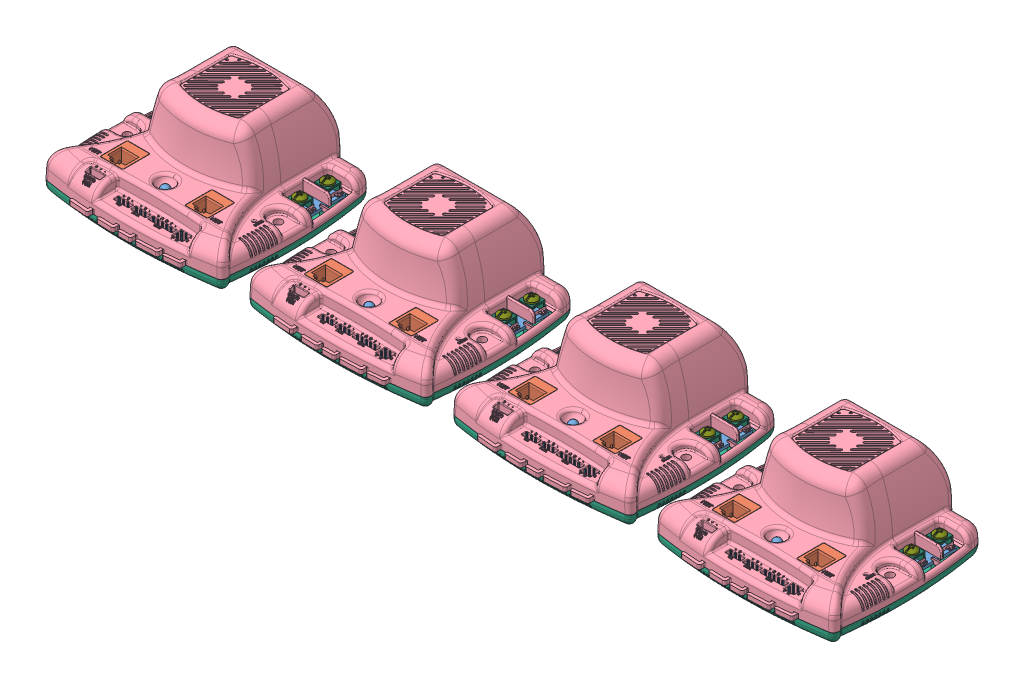
SolidWorks assembly Assem2, configuration Default. Lengths in mm.
Overall size (508 52.96 138.59).
360 component instances, 25 part files, 0 mates.
Components (placement in the parent):
- jaguar-1: jaguar [Default] at (56.1872 37.201 77.5622) size (108.73 52.96 100.91)
  - A-LM-0608-1_PCB_ASM-1: A-LM-0608-1_PCB_ASM [Default] at origin size (88.9 41.9 85.73)
    - C-JAGUAR-PCB-BOARD-1: C-JAGUAR-PCB-BOARD [Default] at origin size (88.9 1.59 85.73)
    - C-L9_RJ11-424106314-1: C-L9_RJ11-424106314 [Default] at (24.9174 8.0645 20.84) x (0 0 -1) z (1 0 0) size (15.88 18.87 15.75)
    - C-L9_RJ11-424106314-2: C-L9_RJ11-424106314 [Default] at (-24.9174 8.0645 20.84) x (0 0 -1) z (1 0 0) size (15.88 18.87 15.75)
    - C-L2-CAPACITOR-1: C-L2-CAPACITOR [Default] at (-0.0004 0 -17.78) size (20 20 20)
    - C-L10_FTS-105-02-X-DV-SA_ANY_ASM-1: C-L10_FTS-105-02-X-DV-SA_ANY_ASM [Default] at (36.0682 -2.8686 -7.8738) x (0 0 1) z (1 0 0) size (6.35 6.3 3.41)
      - T-1S15_-02_FTSH-DV_ANY-1: T-1S15_-02_FTSH-DV_ANY [Default] at (-2.54 -0.635 -0.635) x (0 0 -1) z (1 0 0) size (0.41 6.3 0.41)
      - T-1S15_-02_FTSH-DV_ANY_AF0-1: T-1S15_-02_FTSH-DV_ANY_AF0 [Default] at (2.54 -0.635 0.635) x (0 0 1) z (-1 0 0) size (0.41 6.3 0.41)
      - T-1S15_-02_FTSH-DV_ANY-2: T-1S15_-02_FTSH-DV_ANY [Default] at (-1.27 -0.635 -0.635) x (0 0 -1) z (1 0 0) size (0.41 6.3 0.41)
      - T-1S15_-02_FTSH-DV_ANY-3: T-1S15_-02_FTSH-DV_ANY [Default] at (1.27 -0.635 -0.635) x (0 0 -1) z (1 0 0) size (0.41 6.3 0.41)
      - T-1S15_-02_FTSH-DV_ANY-4: T-1S15_-02_FTSH-DV_ANY [Default] at (0 -0.635 -0.635) x (0 0 -1) z (1 0 0) size (0.41 6.3 0.41)
      - T-1S15_-02_FTSH-DV_ANY-5: T-1S15_-02_FTSH-DV_ANY [Default] at (2.54 -0.635 -0.635) x (0 0 -1) z (1 0 0) size (0.41 6.3 0.41)
      - T-1S15_-02_FTSH-DV_ANY-6: T-1S15_-02_FTSH-DV_ANY [Default] at (1.27 -0.635 0.635) x (0 0 1) z (-1 0 0) size (0.41 6.3 0.41)
      - T-1S15_-02_FTSH-DV_ANY-7: T-1S15_-02_FTSH-DV_ANY [Default] at (0 -0.635 0.635) x (0 0 1) z (-1 0 0) size (0.41 6.3 0.41)
      - T-1S15_-02_FTSH-DV_ANY-8: T-1S15_-02_FTSH-DV_ANY [Default] at (-2.54 -0.635 0.635) x (0 0 1) z (-1 0 0) size (0.41 6.3 0.41)
      - FTS-X-DV_FORMULA_ANY_AF0-1: FTS-X-DV_FORMULA_ANY_AF0 [Default] at origin size (6.35 1 3.41)
      - T-1S15_-02_FTSH-DV_ANY-9: T-1S15_-02_FTSH-DV_ANY [Default] at (-1.27 -0.635 0.635) x (0 0 1) z (-1 0 0) size (0.41 6.3 0.41)
    - L11-SSW-104-01-X-S_ASM-1: L11-SSW-104-01-X-S_ASM [Default] at (-27.6182 0 35.6196) size (8.12 11.05 2.5)
      - SSW-XX-X-1: SSW-XX-X [Default] at origin size (8.12 8.51 2.5)
      - C-08-X-1: C-08-X [Default] at (-1.27 0.508 1.2192) size (1.96 9.53 0.41)
      - C-08-X-2: C-08-X [Default] at (1.27 0.508 1.2192) size (1.96 9.53 0.41)
      - C-08-X-3: C-08-X [Default] at (3.81 0.508 1.2192) size (1.96 9.53 0.41)
    - C-L13-1X3_HEADER_ASM-1: C-L13-1X3_HEADER_ASM [Default] at (-3.5052 1.524 36.8173) size (7.62 10.92 2.54)
      - C-HEADER-3PIN-BODY-1: C-HEADER-3PIN-BODY [Default] at origin size (7.62 2.54 2.54)
      - C-T-HEADER-PIN-1: C-T-HEADER-PIN [Default] at (-6.35 -2.0599 0) x (0 0 1) z (-1 0 0) size (0.64 10.92 0.64)
      - C-T-HEADER-PIN-2: C-T-HEADER-PIN [Default] at (-3.81 -2.0599 0) x (0 0 1) z (-1 0 0) size (0.64 10.92 0.64)
      - C-T-HEADER-PIN-3: C-T-HEADER-PIN [Default] at (-8.89 -2.0599 0) x (0 0 1) z (-1 0 0) size (0.64 10.92 0.64)
    - C-L13-1X3_HEADER_ASM-2: C-L13-1X3_HEADER_ASM [Default] at (6.6548 1.524 36.8173) size (7.62 10.92 2.54)
      - C-HEADER-3PIN-BODY-1: C-HEADER-3PIN-BODY [Default] at origin size (7.62 2.54 2.54)
      - C-T-HEADER-PIN-1: C-T-HEADER-PIN [Default] at (-6.35 -2.0599 0) x (0 0 1) z (-1 0 0) size (0.64 10.92 0.64)
      - C-T-HEADER-PIN-2: C-T-HEADER-PIN [Default] at (-3.81 -2.0599 0) x (0 0 1) z (-1 0 0) size (0.64 10.92 0.64)
      - C-T-HEADER-PIN-3: C-T-HEADER-PIN [Default] at (-8.89 -2.0599 0) x (0 0 1) z (-1 0 0) size (0.64 10.92 0.64)
    - C-L12-1X5_HEADER_ASM-1: C-L12-1X5_HEADER_ASM [Default] at (16.8148 1.524 36.8173) size (12.7 10.92 2.54)
      - C-T-HEADER-PIN-1: C-T-HEADER-PIN [Default] at (-6.35 -2.0599 0) x (0 0 1) z (-1 0 0) size (0.64 10.92 0.64)
      - C-T-HEADER-PIN-2: C-T-HEADER-PIN [Default] at (-3.81 -2.0599 0) x (0 0 1) z (-1 0 0) size (0.64 10.92 0.64)
      - C-T-HEADER-PIN-3: C-T-HEADER-PIN [Default] at (1.27 -2.0599 0) x (0 0 1) z (-1 0 0) size (0.64 10.92 0.64)
      - C-T-HEADER-PIN-4: C-T-HEADER-PIN [Default] at (-8.89 -2.0599 0) x (0 0 1) z (-1 0 0) size (0.64 10.92 0.64)
      - C-T-HEADER-PIN-5: C-T-HEADER-PIN [Default] at (-1.27 -2.0599 0) x (0 0 1) z (-1 0 0) size (0.64 10.92 0.64)
      - C-TSW-XX-S_FORMULA_ANY-5-1: C-TSW-XX-S_FORMULA_ANY-5 [Default] at origin size (12.7 2.54 2.54)
    - C-U1_LUMINARY-CHIP-1: C-U1_LUMINARY-CHIP [Default] at (9.887 0 22.86) size (12 1.45 12)
    - C-BUTTON-SWITCH_ASM-1: C-BUTTON-SWITCH_ASM [Default] at (40.8559 0 10.668) size (6 5 6)
      - C-BS-SWITCH-BASE-1: C-BS-SWITCH-BASE [Default] at origin size (6 4 6)
      - C-BS-EXTENSION-1: C-BS-EXTENSION [Default] at origin size (3.5 1.9 3.5)
    - C-SCREW-TERMINAL-7701_ASM-1: C-SCREW-TERMINAL-7701_ASM [Default] at (39.2172 -5.0038 -17.7792) size (7.87 10.19 7.87)
      - C-ST-7701-BASE-1: C-ST-7701-BASE [Default] at origin size (7.87 7.76 7.87)
      - 6-PH-SCREW-25-1: 6-PH-SCREW-25 [Default] at (0 11.176 0) size (6.86 7.18 6.86)
    - C-SCREW-TERMINAL-7701_ASM-2: C-SCREW-TERMINAL-7701_ASM [Default] at (39.2172 -5.0038 -34.2892) size (7.87 10.19 7.87)
      - C-ST-7701-BASE-1: C-ST-7701-BASE [Default] at origin size (7.87 7.76 7.87)
      - 6-PH-SCREW-25-1: 6-PH-SCREW-25 [Default] at (0 11.176 0) size (6.86 7.18 6.86)
    - C-SCREW-TERMINAL-7701_ASM-3: C-SCREW-TERMINAL-7701_ASM [Default] at (-39.2172 -5.0038 -34.2892) size (7.87 10.19 7.87)
      - C-ST-7701-BASE-1: C-ST-7701-BASE [Default] at origin size (7.87 7.76 7.87)
      - 6-PH-SCREW-25-1: 6-PH-SCREW-25 [Default] at (0 11.176 0) size (6.86 7.18 6.86)
    - C-SCREW-TERMINAL-7701_ASM-4: C-SCREW-TERMINAL-7701_ASM [Default] at (-39.2172 -5.0038 -17.7792) size (7.87 10.19 7.87)
      - C-ST-7701-BASE-1: C-ST-7701-BASE [Default] at origin size (7.87 7.76 7.87)
      - 6-PH-SCREW-25-1: 6-PH-SCREW-25 [Default] at (0 11.176 0) size (6.86 7.18 6.86)
    - C-Q1-Q12_MOSFET-1: C-Q1-Q12_MOSFET [Default] at (0.2539 4.8006 -35.56) x (1 0 0.000017) z (-0.000017 0 1) size (4.57 20.75 10.36)
    - C-Q1-Q12_MOSFET-2: C-Q1-Q12_MOSFET [Default] at (8.9829 4.8006 -32.9335) x (0.866017 0 0.500015) z (-0.500015 0 0.866017) size (4.57 20.75 10.36)
    - C-Q1-Q12_MOSFET-3: C-Q1-Q12_MOSFET [Default] at (8.7964 4.8006 -2.2451) x (-0.866035 0 0.499983) z (-0.499983 0 -0.866035) size (4.57 20.75 10.36)
    - C-Q1-Q12_MOSFET-4: C-Q1-Q12_MOSFET [Default] at (-0.2547 4.8006 0) x (-1 0 -0.000017) z (0.000017 0 -1) size (4.57 20.75 10.36)
    - C-Q1-Q12_MOSFET-5: C-Q1-Q12_MOSFET [Default] at (-9.1106 4.8006 -2.4995) x (-0.866018 0 -0.500013) z (0.500013 0 -0.866018) size (4.57 20.75 10.36)
    - C-Q1-Q12_MOSFET-6: C-Q1-Q12_MOSFET [Default] at (-8.4161 4.8006 -33.3149) x (0.866034 0 -0.499985) z (0.499985 0 0.866034) size (4.57 20.75 10.36)
    - C-Q1-Q12_MOSFET-7: C-Q1-Q12_MOSFET [Default] at (15.4531 4.8006 -26.8897) x (-0.499985 0 -0.866034) z (0.866034 0 -0.499985) size (4.57 20.75 10.36)
    - C-Q1-Q12_MOSFET-8: C-Q1-Q12_MOSFET [Default] at (17.7796 4.8006 -18.0337) x (0.000017 0 -1) z (1 0 0.000017) size (4.57 20.75 10.36)
    - C-Q1-Q12_MOSFET-9: C-Q1-Q12_MOSFET [Default] at (15.7068 4.8006 -9.1097) x (0.500015 0 -0.866017) z (0.866017 0 0.500015) size (4.57 20.75 10.36)
    - C-Q1-Q12_MOSFET-10: C-Q1-Q12_MOSFET [Default] at (-15.4538 4.8006 -8.6703) x (0.499985 0 0.866034) z (-0.866034 0 0.499985) size (4.57 20.75 10.36)
    - C-Q1-Q12_MOSFET-11: C-Q1-Q12_MOSFET [Default] at (-17.7804 4.8006 -17.5263) x (-0.000017 0 1) z (-1 0 -0.000017) size (4.57 20.75 10.36)
    - C-Q1-Q12_MOSFET-12: C-Q1-Q12_MOSFET [Default] at (-15.7075 4.8006 -26.4503) x (-0.500015 0 0.866017) z (-0.866017 0 -0.500015) size (4.57 20.75 10.36)
    - C-Q1-Q12_MOSFET-13: C-Q1-Q12_MOSFET [Default] at (0.2539 4.8006 -35.56) size (4.57 20.75 10.36)
    - P-LM-0608-1-003_MOSFET-RING-1: P-LM-0608-1-003_MOSFET-RING [Default] at origin size (51.07 7.69 51.07)
    - I15_59-1: I15_59 [Default] at (0 5.8 22.11) size (5.9 13.4 5.84)
    - D4010-1: D4010 [Default] at (-0.0004 25.4 -17.78) x (0.000017 0 -1) z (-1 0 -0.000017) size (40 11.76 40)
    - C-L13-1X2_HEADER_ASM-1: C-L13-1X2_HEADER_ASM [Default] at (32.0548 1.524 35.5473) size (5.08 10.92 2.54)
      - C-HEADER-2PIN-BODY-1: C-HEADER-2PIN-BODY [Default] at origin size (5.08 2.54 2.54)
      - C-T-HEADER-PIN-1: C-T-HEADER-PIN [Default] at (-6.35 -2.0599 0) x (0 0 1) z (-1 0 0) size (0.64 10.92 0.64)
      - C-T-HEADER-PIN-2: C-T-HEADER-PIN [Default] at (-8.89 -2.0599 0) x (0 0 1) z (-1 0 0) size (0.64 10.92 0.64)
    - C-L13-1X2_HEADER_ASM-2: C-L13-1X2_HEADER_ASM [Default] at (32.0548 1.524 38.0873) size (5.08 10.92 2.54)
      - C-HEADER-2PIN-BODY-1: C-HEADER-2PIN-BODY [Default] at origin size (5.08 2.54 2.54)
      - C-T-HEADER-PIN-1: C-T-HEADER-PIN [Default] at (-6.35 -2.0599 0) x (0 0 1) z (-1 0 0) size (0.64 10.92 0.64)
      - C-T-HEADER-PIN-2: C-T-HEADER-PIN [Default] at (-8.89 -2.0599 0) x (0 0 1) z (-1 0 0) size (0.64 10.92 0.64)
  - 217-3367-001-1: 217-3367-001 [Default] at origin size (108.73 46.49 100.91)
  - 4-PH-SCREW-58-1: 4-PH-SCREW-58 [Default] at (-16.0007 25.4 -1.7803) x (-1 0 0) z (0 0 1) size (5.56 17.84 5.56)
  - 217-3367-002-1: 217-3367-002 [Default] at origin size (107.95 8.08 97.61)
  - 4-PH-SCREW-5-1: 4-PH-SCREW-5 [Default] at (46.482 -3.7084 36.4715) x (-1 0 0) z (0 0 1) size (5.56 14.66 5.56)
  - 4-PH-SCREW-5-2: 4-PH-SCREW-5 [Default] at (43.9521 -3.7084 -44.717) x (-1 0 0) z (0 0 1) size (5.56 14.66 5.56)
  - 4-PH-SCREW-5-3: 4-PH-SCREW-5 [Default] at (-43.9521 -3.7084 -44.717) x (-1 0 0) z (0 0 1) size (5.56 14.66 5.56)
  - 4-PH-SCREW-5-4: 4-PH-SCREW-5 [Default] at (-46.482 -3.7084 36.4715) x (-1 0 0) z (0 0 1) size (5.56 14.66 5.56)
  - 4-PH-SCREW-58-2: 4-PH-SCREW-58 [Default] at (-16.0001 25.4 -33.7803) x (-1 0 0) z (0 0 1) size (5.56 17.84 5.56)
  - 4-PH-SCREW-58-3: 4-PH-SCREW-58 [Default] at (15.9999 25.4 -33.7797) x (-1 0 0) z (0 0 1) size (5.56 17.84 5.56)
  - 4-PH-SCREW-58-4: 4-PH-SCREW-58 [Default] at (15.9993 25.4 -1.7797) x (-1 0 0) z (0 0 1) size (5.56 17.84 5.56)
- jaguar-2: jaguar [Default] at (176.1872 37.201 77.5622) size (108.73 52.96 100.91)
  - A-LM-0608-1_PCB_ASM-1: A-LM-0608-1_PCB_ASM [Default] at origin size (88.9 41.9 85.73)
    - C-JAGUAR-PCB-BOARD-1: C-JAGUAR-PCB-BOARD [Default] at origin size (88.9 1.59 85.73)
    - C-L9_RJ11-424106314-1: C-L9_RJ11-424106314 [Default] at (24.9174 8.0645 20.84) x (0 0 -1) z (1 0 0) size (15.88 18.87 15.75)
    - C-L9_RJ11-424106314-2: C-L9_RJ11-424106314 [Default] at (-24.9174 8.0645 20.84) x (0 0 -1) z (1 0 0) size (15.88 18.87 15.75)
    - C-L2-CAPACITOR-1: C-L2-CAPACITOR [Default] at (-0.0004 0 -17.78) size (20 20 20)
    - C-L10_FTS-105-02-X-DV-SA_ANY_ASM-1: C-L10_FTS-105-02-X-DV-SA_ANY_ASM [Default] at (36.0682 -2.8686 -7.8738) x (0 0 1) z (1 0 0) size (6.35 6.3 3.41)
      - T-1S15_-02_FTSH-DV_ANY-1: T-1S15_-02_FTSH-DV_ANY [Default] at (-2.54 -0.635 -0.635) x (0 0 -1) z (1 0 0) size (0.41 6.3 0.41)
      - T-1S15_-02_FTSH-DV_ANY_AF0-1: T-1S15_-02_FTSH-DV_ANY_AF0 [Default] at (2.54 -0.635 0.635) x (0 0 1) z (-1 0 0) size (0.41 6.3 0.41)
      - T-1S15_-02_FTSH-DV_ANY-2: T-1S15_-02_FTSH-DV_ANY [Default] at (-1.27 -0.635 -0.635) x (0 0 -1) z (1 0 0) size (0.41 6.3 0.41)
      - T-1S15_-02_FTSH-DV_ANY-3: T-1S15_-02_FTSH-DV_ANY [Default] at (1.27 -0.635 -0.635) x (0 0 -1) z (1 0 0) size (0.41 6.3 0.41)
      - T-1S15_-02_FTSH-DV_ANY-4: T-1S15_-02_FTSH-DV_ANY [Default] at (0 -0.635 -0.635) x (0 0 -1) z (1 0 0) size (0.41 6.3 0.41)
      - T-1S15_-02_FTSH-DV_ANY-5: T-1S15_-02_FTSH-DV_ANY [Default] at (2.54 -0.635 -0.635) x (0 0 -1) z (1 0 0) size (0.41 6.3 0.41)
      - T-1S15_-02_FTSH-DV_ANY-6: T-1S15_-02_FTSH-DV_ANY [Default] at (1.27 -0.635 0.635) x (0 0 1) z (-1 0 0) size (0.41 6.3 0.41)
      - T-1S15_-02_FTSH-DV_ANY-7: T-1S15_-02_FTSH-DV_ANY [Default] at (0 -0.635 0.635) x (0 0 1) z (-1 0 0) size (0.41 6.3 0.41)
      - T-1S15_-02_FTSH-DV_ANY-8: T-1S15_-02_FTSH-DV_ANY [Default] at (-2.54 -0.635 0.635) x (0 0 1) z (-1 0 0) size (0.41 6.3 0.41)
      - FTS-X-DV_FORMULA_ANY_AF0-1: FTS-X-DV_FORMULA_ANY_AF0 [Default] at origin size (6.35 1 3.41)
      - T-1S15_-02_FTSH-DV_ANY-9: T-1S15_-02_FTSH-DV_ANY [Default] at (-1.27 -0.635 0.635) x (0 0 1) z (-1 0 0) size (0.41 6.3 0.41)
    - L11-SSW-104-01-X-S_ASM-1: L11-SSW-104-01-X-S_ASM [Default] at (-27.6182 0 35.6196) size (8.12 11.05 2.5)
      - SSW-XX-X-1: SSW-XX-X [Default] at origin size (8.12 8.51 2.5)
      - C-08-X-1: C-08-X [Default] at (-1.27 0.508 1.2192) size (1.96 9.53 0.41)
      - C-08-X-2: C-08-X [Default] at (1.27 0.508 1.2192) size (1.96 9.53 0.41)
      - C-08-X-3: C-08-X [Default] at (3.81 0.508 1.2192) size (1.96 9.53 0.41)
    - C-L13-1X3_HEADER_ASM-1: C-L13-1X3_HEADER_ASM [Default] at (-3.5052 1.524 36.8173) size (7.62 10.92 2.54)
      - C-HEADER-3PIN-BODY-1: C-HEADER-3PIN-BODY [Default] at origin size (7.62 2.54 2.54)
      - C-T-HEADER-PIN-1: C-T-HEADER-PIN [Default] at (-6.35 -2.0599 0) x (0 0 1) z (-1 0 0) size (0.64 10.92 0.64)
      - C-T-HEADER-PIN-2: C-T-HEADER-PIN [Default] at (-3.81 -2.0599 0) x (0 0 1) z (-1 0 0) size (0.64 10.92 0.64)
      - C-T-HEADER-PIN-3: C-T-HEADER-PIN [Default] at (-8.89 -2.0599 0) x (0 0 1) z (-1 0 0) size (0.64 10.92 0.64)
    - C-L13-1X3_HEADER_ASM-2: C-L13-1X3_HEADER_ASM [Default] at (6.6548 1.524 36.8173) size (7.62 10.92 2.54)
      - C-HEADER-3PIN-BODY-1: C-HEADER-3PIN-BODY [Default] at origin size (7.62 2.54 2.54)
      - C-T-HEADER-PIN-1: C-T-HEADER-PIN [Default] at (-6.35 -2.0599 0) x (0 0 1) z (-1 0 0) size (0.64 10.92 0.64)
      - C-T-HEADER-PIN-2: C-T-HEADER-PIN [Default] at (-3.81 -2.0599 0) x (0 0 1) z (-1 0 0) size (0.64 10.92 0.64)
      - C-T-HEADER-PIN-3: C-T-HEADER-PIN [Default] at (-8.89 -2.0599 0) x (0 0 1) z (-1 0 0) size (0.64 10.92 0.64)
    - C-L12-1X5_HEADER_ASM-1: C-L12-1X5_HEADER_ASM [Default] at (16.8148 1.524 36.8173) size (12.7 10.92 2.54)
      - C-T-HEADER-PIN-1: C-T-HEADER-PIN [Default] at (-6.35 -2.0599 0) x (0 0 1) z (-1 0 0) size (0.64 10.92 0.64)
      - C-T-HEADER-PIN-2: C-T-HEADER-PIN [Default] at (-3.81 -2.0599 0) x (0 0 1) z (-1 0 0) size (0.64 10.92 0.64)
      - C-T-HEADER-PIN-3: C-T-HEADER-PIN [Default] at (1.27 -2.0599 0) x (0 0 1) z (-1 0 0) size (0.64 10.92 0.64)
      - C-T-HEADER-PIN-4: C-T-HEADER-PIN [Default] at (-8.89 -2.0599 0) x (0 0 1) z (-1 0 0) size (0.64 10.92 0.64)
      - C-T-HEADER-PIN-5: C-T-HEADER-PIN [Default] at (-1.27 -2.0599 0) x (0 0 1) z (-1 0 0) size (0.64 10.92 0.64)
      - C-TSW-XX-S_FORMULA_ANY-5-1: C-TSW-XX-S_FORMULA_ANY-5 [Default] at origin size (12.7 2.54 2.54)
    - C-U1_LUMINARY-CHIP-1: C-U1_LUMINARY-CHIP [Default] at (9.887 0 22.86) size (12 1.45 12)
    - C-BUTTON-SWITCH_ASM-1: C-BUTTON-SWITCH_ASM [Default] at (40.8559 0 10.668) size (6 5 6)
      - C-BS-SWITCH-BASE-1: C-BS-SWITCH-BASE [Default] at origin size (6 4 6)
      - C-BS-EXTENSION-1: C-BS-EXTENSION [Default] at origin size (3.5 1.9 3.5)
    - C-SCREW-TERMINAL-7701_ASM-1: C-SCREW-TERMINAL-7701_ASM [Default] at (39.2172 -5.0038 -17.7792) size (7.87 10.19 7.87)
      - C-ST-7701-BASE-1: C-ST-7701-BASE [Default] at origin size (7.87 7.76 7.87)
      - 6-PH-SCREW-25-1: 6-PH-SCREW-25 [Default] at (0 11.176 0) size (6.86 7.18 6.86)
    - C-SCREW-TERMINAL-7701_ASM-2: C-SCREW-TERMINAL-7701_ASM [Default] at (39.2172 -5.0038 -34.2892) size (7.87 10.19 7.87)
      - C-ST-7701-BASE-1: C-ST-7701-BASE [Default] at origin size (7.87 7.76 7.87)
      - 6-PH-SCREW-25-1: 6-PH-SCREW-25 [Default] at (0 11.176 0) size (6.86 7.18 6.86)
    - C-SCREW-TERMINAL-7701_ASM-3: C-SCREW-TERMINAL-7701_ASM [Default] at (-39.2172 -5.0038 -34.2892) size (7.87 10.19 7.87)
      - C-ST-7701-BASE-1: C-ST-7701-BASE [Default] at origin size (7.87 7.76 7.87)
      - 6-PH-SCREW-25-1: 6-PH-SCREW-25 [Default] at (0 11.176 0) size (6.86 7.18 6.86)
    - C-SCREW-TERMINAL-7701_ASM-4: C-SCREW-TERMINAL-7701_ASM [Default] at (-39.2172 -5.0038 -17.7792) size (7.87 10.19 7.87)
      - C-ST-7701-BASE-1: C-ST-7701-BASE [Default] at origin size (7.87 7.76 7.87)
      - 6-PH-SCREW-25-1: 6-PH-SCREW-25 [Default] at (0 11.176 0) size (6.86 7.18 6.86)
    - C-Q1-Q12_MOSFET-1: C-Q1-Q12_MOSFET [Default] at (0.2539 4.8006 -35.56) x (1 0 0.000017) z (-0.000017 0 1) size (4.57 20.75 10.36)
    - C-Q1-Q12_MOSFET-2: C-Q1-Q12_MOSFET [Default] at (8.9829 4.8006 -32.9335) x (0.866017 0 0.500015) z (-0.500015 0 0.866017) size (4.57 20.75 10.36)
    - C-Q1-Q12_MOSFET-3: C-Q1-Q12_MOSFET [Default] at (8.7964 4.8006 -2.2451) x (-0.866035 0 0.499983) z (-0.499983 0 -0.866035) size (4.57 20.75 10.36)
    - C-Q1-Q12_MOSFET-4: C-Q1-Q12_MOSFET [Default] at (-0.2547 4.8006 0) x (-1 0 -0.000017) z (0.000017 0 -1) size (4.57 20.75 10.36)
    - C-Q1-Q12_MOSFET-5: C-Q1-Q12_MOSFET [Default] at (-9.1106 4.8006 -2.4995) x (-0.866018 0 -0.500013) z (0.500013 0 -0.866018) size (4.57 20.75 10.36)
    - C-Q1-Q12_MOSFET-6: C-Q1-Q12_MOSFET [Default] at (-8.4161 4.8006 -33.3149) x (0.866034 0 -0.499985) z (0.499985 0 0.866034) size (4.57 20.75 10.36)
    - C-Q1-Q12_MOSFET-7: C-Q1-Q12_MOSFET [Default] at (15.4531 4.8006 -26.8897) x (-0.499985 0 -0.866034) z (0.866034 0 -0.499985) size (4.57 20.75 10.36)
    - C-Q1-Q12_MOSFET-8: C-Q1-Q12_MOSFET [Default] at (17.7796 4.8006 -18.0337) x (0.000017 0 -1) z (1 0 0.000017) size (4.57 20.75 10.36)
    - C-Q1-Q12_MOSFET-9: C-Q1-Q12_MOSFET [Default] at (15.7068 4.8006 -9.1097) x (0.500015 0 -0.866017) z (0.866017 0 0.500015) size (4.57 20.75 10.36)
    - C-Q1-Q12_MOSFET-10: C-Q1-Q12_MOSFET [Default] at (-15.4538 4.8006 -8.6703) x (0.499985 0 0.866034) z (-0.866034 0 0.499985) size (4.57 20.75 10.36)
    - C-Q1-Q12_MOSFET-11: C-Q1-Q12_MOSFET [Default] at (-17.7804 4.8006 -17.5263) x (-0.000017 0 1) z (-1 0 -0.000017) size (4.57 20.75 10.36)
    - C-Q1-Q12_MOSFET-12: C-Q1-Q12_MOSFET [Default] at (-15.7075 4.8006 -26.4503) x (-0.500015 0 0.866017) z (-0.866017 0 -0.500015) size (4.57 20.75 10.36)
    - C-Q1-Q12_MOSFET-13: C-Q1-Q12_MOSFET [Default] at (0.2539 4.8006 -35.56) size (4.57 20.75 10.36)
    - P-LM-0608-1-003_MOSFET-RING-1: P-LM-0608-1-003_MOSFET-RING [Default] at origin size (51.07 7.69 51.07)
    - I15_59-1: I15_59 [Default] at (0 5.8 22.11) size (5.9 13.4 5.84)
    - D4010-1: D4010 [Default] at (-0.0004 25.4 -17.78) x (0.000017 0 -1) z (-1 0 -0.000017) size (40 11.76 40)
    - C-L13-1X2_HEADER_ASM-1: C-L13-1X2_HEADER_ASM [Default] at (32.0548 1.524 35.5473) size (5.08 10.92 2.54)
      - C-HEADER-2PIN-BODY-1: C-HEADER-2PIN-BODY [Default] at origin size (5.08 2.54 2.54)
      - C-T-HEADER-PIN-1: C-T-HEADER-PIN [Default] at (-6.35 -2.0599 0) x (0 0 1) z (-1 0 0) size (0.64 10.92 0.64)
      - C-T-HEADER-PIN-2: C-T-HEADER-PIN [Default] at (-8.89 -2.0599 0) x (0 0 1) z (-1 0 0) size (0.64 10.92 0.64)
    - C-L13-1X2_HEADER_ASM-2: C-L13-1X2_HEADER_ASM [Default] at (32.0548 1.524 38.0873) size (5.08 10.92 2.54)
      - C-HEADER-2PIN-BODY-1: C-HEADER-2PIN-BODY [Default] at origin size (5.08 2.54 2.54)
      - C-T-HEADER-PIN-1: C-T-HEADER-PIN [Default] at (-6.35 -2.0599 0) x (0 0 1) z (-1 0 0) size (0.64 10.92 0.64)
      - C-T-HEADER-PIN-2: C-T-HEADER-PIN [Default] at (-8.89 -2.0599 0) x (0 0 1) z (-1 0 0) size (0.64 10.92 0.64)
  - 217-3367-001-1: 217-3367-001 [Default] at origin size (108.73 46.49 100.91)
  - 4-PH-SCREW-58-1: 4-PH-SCREW-58 [Default] at (-16.0007 25.4 -1.7803) x (-1 0 0) z (0 0 1) size (5.56 17.84 5.56)
  - 217-3367-002-1: 217-3367-002 [Default] at origin size (107.95 8.08 97.61)
  - 4-PH-SCREW-5-1: 4-PH-SCREW-5 [Default] at (46.482 -3.7084 36.4715) x (-1 0 0) z (0 0 1) size (5.56 14.66 5.56)
  - 4-PH-SCREW-5-2: 4-PH-SCREW-5 [Default] at (43.9521 -3.7084 -44.717) x (-1 0 0) z (0 0 1) size (5.56 14.66 5.56)
  - 4-PH-SCREW-5-3: 4-PH-SCREW-5 [Default] at (-43.9521 -3.7084 -44.717) x (-1 0 0) z (0 0 1) size (5.56 14.66 5.56)
  - 4-PH-SCREW-5-4: 4-PH-SCREW-5 [Default] at (-46.482 -3.7084 36.4715) x (-1 0 0) z (0 0 1) size (5.56 14.66 5.56)
  - 4-PH-SCREW-58-2: 4-PH-SCREW-58 [Default] at (-16.0001 25.4 -33.7803) x (-1 0 0) z (0 0 1) size (5.56 17.84 5.56)
  - 4-PH-SCREW-58-3: 4-PH-SCREW-58 [Default] at (15.9999 25.4 -33.7797) x (-1 0 0) z (0 0 1) size (5.56 17.84 5.56)
  - 4-PH-SCREW-58-4: 4-PH-SCREW-58 [Default] at (15.9993 25.4 -1.7797) x (-1 0 0) z (0 0 1) size (5.56 17.84 5.56)
- jaguar-3: jaguar [Default] at (296.1872 37.201 77.5622) size (108.73 52.96 100.91)
  - A-LM-0608-1_PCB_ASM-1: A-LM-0608-1_PCB_ASM [Default] at origin size (88.9 41.9 85.73)
    - C-JAGUAR-PCB-BOARD-1: C-JAGUAR-PCB-BOARD [Default] at origin size (88.9 1.59 85.73)
    - C-L9_RJ11-424106314-1: C-L9_RJ11-424106314 [Default] at (24.9174 8.0645 20.84) x (0 0 -1) z (1 0 0) size (15.88 18.87 15.75)
    - C-L9_RJ11-424106314-2: C-L9_RJ11-424106314 [Default] at (-24.9174 8.0645 20.84) x (0 0 -1) z (1 0 0) size (15.88 18.87 15.75)
    - C-L2-CAPACITOR-1: C-L2-CAPACITOR [Default] at (-0.0004 0 -17.78) size (20 20 20)
    - C-L10_FTS-105-02-X-DV-SA_ANY_ASM-1: C-L10_FTS-105-02-X-DV-SA_ANY_ASM [Default] at (36.0682 -2.8686 -7.8738) x (0 0 1) z (1 0 0) size (6.35 6.3 3.41)
      - T-1S15_-02_FTSH-DV_ANY-1: T-1S15_-02_FTSH-DV_ANY [Default] at (-2.54 -0.635 -0.635) x (0 0 -1) z (1 0 0) size (0.41 6.3 0.41)
      - T-1S15_-02_FTSH-DV_ANY_AF0-1: T-1S15_-02_FTSH-DV_ANY_AF0 [Default] at (2.54 -0.635 0.635) x (0 0 1) z (-1 0 0) size (0.41 6.3 0.41)
      - T-1S15_-02_FTSH-DV_ANY-2: T-1S15_-02_FTSH-DV_ANY [Default] at (-1.27 -0.635 -0.635) x (0 0 -1) z (1 0 0) size (0.41 6.3 0.41)
      - T-1S15_-02_FTSH-DV_ANY-3: T-1S15_-02_FTSH-DV_ANY [Default] at (1.27 -0.635 -0.635) x (0 0 -1) z (1 0 0) size (0.41 6.3 0.41)
      - T-1S15_-02_FTSH-DV_ANY-4: T-1S15_-02_FTSH-DV_ANY [Default] at (0 -0.635 -0.635) x (0 0 -1) z (1 0 0) size (0.41 6.3 0.41)
      - T-1S15_-02_FTSH-DV_ANY-5: T-1S15_-02_FTSH-DV_ANY [Default] at (2.54 -0.635 -0.635) x (0 0 -1) z (1 0 0) size (0.41 6.3 0.41)
      - T-1S15_-02_FTSH-DV_ANY-6: T-1S15_-02_FTSH-DV_ANY [Default] at (1.27 -0.635 0.635) x (0 0 1) z (-1 0 0) size (0.41 6.3 0.41)
      - T-1S15_-02_FTSH-DV_ANY-7: T-1S15_-02_FTSH-DV_ANY [Default] at (0 -0.635 0.635) x (0 0 1) z (-1 0 0) size (0.41 6.3 0.41)
      - T-1S15_-02_FTSH-DV_ANY-8: T-1S15_-02_FTSH-DV_ANY [Default] at (-2.54 -0.635 0.635) x (0 0 1) z (-1 0 0) size (0.41 6.3 0.41)
      - FTS-X-DV_FORMULA_ANY_AF0-1: FTS-X-DV_FORMULA_ANY_AF0 [Default] at origin size (6.35 1 3.41)
      - T-1S15_-02_FTSH-DV_ANY-9: T-1S15_-02_FTSH-DV_ANY [Default] at (-1.27 -0.635 0.635) x (0 0 1) z (-1 0 0) size (0.41 6.3 0.41)
    - L11-SSW-104-01-X-S_ASM-1: L11-SSW-104-01-X-S_ASM [Default] at (-27.6182 0 35.6196) size (8.12 11.05 2.5)
      - SSW-XX-X-1: SSW-XX-X [Default] at origin size (8.12 8.51 2.5)
      - C-08-X-1: C-08-X [Default] at (-1.27 0.508 1.2192) size (1.96 9.53 0.41)
      - C-08-X-2: C-08-X [Default] at (1.27 0.508 1.2192) size (1.96 9.53 0.41)
      - C-08-X-3: C-08-X [Default] at (3.81 0.508 1.2192) size (1.96 9.53 0.41)
    - C-L13-1X3_HEADER_ASM-1: C-L13-1X3_HEADER_ASM [Default] at (-3.5052 1.524 36.8173) size (7.62 10.92 2.54)
      - C-HEADER-3PIN-BODY-1: C-HEADER-3PIN-BODY [Default] at origin size (7.62 2.54 2.54)
      - C-T-HEADER-PIN-1: C-T-HEADER-PIN [Default] at (-6.35 -2.0599 0) x (0 0 1) z (-1 0 0) size (0.64 10.92 0.64)
      - C-T-HEADER-PIN-2: C-T-HEADER-PIN [Default] at (-3.81 -2.0599 0) x (0 0 1) z (-1 0 0) size (0.64 10.92 0.64)
      - C-T-HEADER-PIN-3: C-T-HEADER-PIN [Default] at (-8.89 -2.0599 0) x (0 0 1) z (-1 0 0) size (0.64 10.92 0.64)
    - C-L13-1X3_HEADER_ASM-2: C-L13-1X3_HEADER_ASM [Default] at (6.6548 1.524 36.8173) size (7.62 10.92 2.54)
      - C-HEADER-3PIN-BODY-1: C-HEADER-3PIN-BODY [Default] at origin size (7.62 2.54 2.54)
      - C-T-HEADER-PIN-1: C-T-HEADER-PIN [Default] at (-6.35 -2.0599 0) x (0 0 1) z (-1 0 0) size (0.64 10.92 0.64)
      - C-T-HEADER-PIN-2: C-T-HEADER-PIN [Default] at (-3.81 -2.0599 0) x (0 0 1) z (-1 0 0) size (0.64 10.92 0.64)
      - C-T-HEADER-PIN-3: C-T-HEADER-PIN [Default] at (-8.89 -2.0599 0) x (0 0 1) z (-1 0 0) size (0.64 10.92 0.64)
    - C-L12-1X5_HEADER_ASM-1: C-L12-1X5_HEADER_ASM [Default] at (16.8148 1.524 36.8173) size (12.7 10.92 2.54)
      - C-T-HEADER-PIN-1: C-T-HEADER-PIN [Default] at (-6.35 -2.0599 0) x (0 0 1) z (-1 0 0) size (0.64 10.92 0.64)
      - C-T-HEADER-PIN-2: C-T-HEADER-PIN [Default] at (-3.81 -2.0599 0) x (0 0 1) z (-1 0 0) size (0.64 10.92 0.64)
      - C-T-HEADER-PIN-3: C-T-HEADER-PIN [Default] at (1.27 -2.0599 0) x (0 0 1) z (-1 0 0) size (0.64 10.92 0.64)
      - C-T-HEADER-PIN-4: C-T-HEADER-PIN [Default] at (-8.89 -2.0599 0) x (0 0 1) z (-1 0 0) size (0.64 10.92 0.64)
      - C-T-HEADER-PIN-5: C-T-HEADER-PIN [Default] at (-1.27 -2.0599 0) x (0 0 1) z (-1 0 0) size (0.64 10.92 0.64)
      - C-TSW-XX-S_FORMULA_ANY-5-1: C-TSW-XX-S_FORMULA_ANY-5 [Default] at origin size (12.7 2.54 2.54)
    - C-U1_LUMINARY-CHIP-1: C-U1_LUMINARY-CHIP [Default] at (9.887 0 22.86) size (12 1.45 12)
    - C-BUTTON-SWITCH_ASM-1: C-BUTTON-SWITCH_ASM [Default] at (40.8559 0 10.668) size (6 5 6)
      - C-BS-SWITCH-BASE-1: C-BS-SWITCH-BASE [Default] at origin size (6 4 6)
      - C-BS-EXTENSION-1: C-BS-EXTENSION [Default] at origin size (3.5 1.9 3.5)
    - C-SCREW-TERMINAL-7701_ASM-1: C-SCREW-TERMINAL-7701_ASM [Default] at (39.2172 -5.0038 -17.7792) size (7.87 10.19 7.87)
      - C-ST-7701-BASE-1: C-ST-7701-BASE [Default] at origin size (7.87 7.76 7.87)
      - 6-PH-SCREW-25-1: 6-PH-SCREW-25 [Default] at (0 11.176 0) size (6.86 7.18 6.86)
    - C-SCREW-TERMINAL-7701_ASM-2: C-SCREW-TERMINAL-7701_ASM [Default] at (39.2172 -5.0038 -34.2892) size (7.87 10.19 7.87)
      - C-ST-7701-BASE-1: C-ST-7701-BASE [Default] at origin size (7.87 7.76 7.87)
      - 6-PH-SCREW-25-1: 6-PH-SCREW-25 [Default] at (0 11.176 0) size (6.86 7.18 6.86)
    - C-SCREW-TERMINAL-7701_ASM-3: C-SCREW-TERMINAL-7701_ASM [Default] at (-39.2172 -5.0038 -34.2892) size (7.87 10.19 7.87)
      - C-ST-7701-BASE-1: C-ST-7701-BASE [Default] at origin size (7.87 7.76 7.87)
      - 6-PH-SCREW-25-1: 6-PH-SCREW-25 [Default] at (0 11.176 0) size (6.86 7.18 6.86)
    - C-SCREW-TERMINAL-7701_ASM-4: C-SCREW-TERMINAL-7701_ASM [Default] at (-39.2172 -5.0038 -17.7792) size (7.87 10.19 7.87)
      - C-ST-7701-BASE-1: C-ST-7701-BASE [Default] at origin size (7.87 7.76 7.87)
      - 6-PH-SCREW-25-1: 6-PH-SCREW-25 [Default] at (0 11.176 0) size (6.86 7.18 6.86)
    - C-Q1-Q12_MOSFET-1: C-Q1-Q12_MOSFET [Default] at (0.2539 4.8006 -35.56) x (1 0 0.000017) z (-0.000017 0 1) size (4.57 20.75 10.36)
    - C-Q1-Q12_MOSFET-2: C-Q1-Q12_MOSFET [Default] at (8.9829 4.8006 -32.9335) x (0.866017 0 0.500015) z (-0.500015 0 0.866017) size (4.57 20.75 10.36)
    - C-Q1-Q12_MOSFET-3: C-Q1-Q12_MOSFET [Default] at (8.7964 4.8006 -2.2451) x (-0.866035 0 0.499983) z (-0.499983 0 -0.866035) size (4.57 20.75 10.36)
    - C-Q1-Q12_MOSFET-4: C-Q1-Q12_MOSFET [Default] at (-0.2547 4.8006 0) x (-1 0 -0.000017) z (0.000017 0 -1) size (4.57 20.75 10.36)
    - C-Q1-Q12_MOSFET-5: C-Q1-Q12_MOSFET [Default] at (-9.1106 4.8006 -2.4995) x (-0.866018 0 -0.500013) z (0.500013 0 -0.866018) size (4.57 20.75 10.36)
    - C-Q1-Q12_MOSFET-6: C-Q1-Q12_MOSFET [Default] at (-8.4161 4.8006 -33.3149) x (0.866034 0 -0.499985) z (0.499985 0 0.866034) size (4.57 20.75 10.36)
    - C-Q1-Q12_MOSFET-7: C-Q1-Q12_MOSFET [Default] at (15.4531 4.8006 -26.8897) x (-0.499985 0 -0.866034) z (0.866034 0 -0.499985) size (4.57 20.75 10.36)
    - C-Q1-Q12_MOSFET-8: C-Q1-Q12_MOSFET [Default] at (17.7796 4.8006 -18.0337) x (0.000017 0 -1) z (1 0 0.000017) size (4.57 20.75 10.36)
    - C-Q1-Q12_MOSFET-9: C-Q1-Q12_MOSFET [Default] at (15.7068 4.8006 -9.1097) x (0.500015 0 -0.866017) z (0.866017 0 0.500015) size (4.57 20.75 10.36)
    - C-Q1-Q12_MOSFET-10: C-Q1-Q12_MOSFET [Default] at (-15.4538 4.8006 -8.6703) x (0.499985 0 0.866034) z (-0.866034 0 0.499985) size (4.57 20.75 10.36)
    - C-Q1-Q12_MOSFET-11: C-Q1-Q12_MOSFET [Default] at (-17.7804 4.8006 -17.5263) x (-0.000017 0 1) z (-1 0 -0.000017) size (4.57 20.75 10.36)
    - C-Q1-Q12_MOSFET-12: C-Q1-Q12_MOSFET [Default] at (-15.7075 4.8006 -26.4503) x (-0.500015 0 0.866017) z (-0.866017 0 -0.500015) size (4.57 20.75 10.36)
    - C-Q1-Q12_MOSFET-13: C-Q1-Q12_MOSFET [Default] at (0.2539 4.8006 -35.56) size (4.57 20.75 10.36)
    - P-LM-0608-1-003_MOSFET-RING-1: P-LM-0608-1-003_MOSFET-RING [Default] at origin size (51.07 7.69 51.07)
    - I15_59-1: I15_59 [Default] at (0 5.8 22.11) size (5.9 13.4 5.84)
    - D4010-1: D4010 [Default] at (-0.0004 25.4 -17.78) x (0.000017 0 -1) z (-1 0 -0.000017) size (40 11.76 40)
    - C-L13-1X2_HEADER_ASM-1: C-L13-1X2_HEADER_ASM [Default] at (32.0548 1.524 35.5473) size (5.08 10.92 2.54)
      - C-HEADER-2PIN-BODY-1: C-HEADER-2PIN-BODY [Default] at origin size (5.08 2.54 2.54)
      - C-T-HEADER-PIN-1: C-T-HEADER-PIN [Default] at (-6.35 -2.0599 0) x (0 0 1) z (-1 0 0) size (0.64 10.92 0.64)
      - C-T-HEADER-PIN-2: C-T-HEADER-PIN [Default] at (-8.89 -2.0599 0) x (0 0 1) z (-1 0 0) size (0.64 10.92 0.64)
    - C-L13-1X2_HEADER_ASM-2: C-L13-1X2_HEADER_ASM [Default] at (32.0548 1.524 38.0873) size (5.08 10.92 2.54)
      - C-HEADER-2PIN-BODY-1: C-HEADER-2PIN-BODY [Default] at origin size (5.08 2.54 2.54)
      - C-T-HEADER-PIN-1: C-T-HEADER-PIN [Default] at (-6.35 -2.0599 0) x (0 0 1) z (-1 0 0) size (0.64 10.92 0.64)
      - C-T-HEADER-PIN-2: C-T-HEADER-PIN [Default] at (-8.89 -2.0599 0) x (0 0 1) z (-1 0 0) size (0.64 10.92 0.64)
  - 217-3367-001-1: 217-3367-001 [Default] at origin size (108.73 46.49 100.91)
  - 4-PH-SCREW-58-1: 4-PH-SCREW-58 [Default] at (-16.0007 25.4 -1.7803) x (-1 0 0) z (0 0 1) size (5.56 17.84 5.56)
  - 217-3367-002-1: 217-3367-002 [Default] at origin size (107.95 8.08 97.61)
  - 4-PH-SCREW-5-1: 4-PH-SCREW-5 [Default] at (46.482 -3.7084 36.4715) x (-1 0 0) z (0 0 1) size (5.56 14.66 5.56)
  - 4-PH-SCREW-5-2: 4-PH-SCREW-5 [Default] at (43.9521 -3.7084 -44.717) x (-1 0 0) z (0 0 1) size (5.56 14.66 5.56)
  - 4-PH-SCREW-5-3: 4-PH-SCREW-5 [Default] at (-43.9521 -3.7084 -44.717) x (-1 0 0) z (0 0 1) size (5.56 14.66 5.56)
  - 4-PH-SCREW-5-4: 4-PH-SCREW-5 [Default] at (-46.482 -3.7084 36.4715) x (-1 0 0) z (0 0 1) size (5.56 14.66 5.56)
  - 4-PH-SCREW-58-2: 4-PH-SCREW-58 [Default] at (-16.0001 25.4 -33.7803) x (-1 0 0) z (0 0 1) size (5.56 17.84 5.56)
  - 4-PH-SCREW-58-3: 4-PH-SCREW-58 [Default] at (15.9999 25.4 -33.7797) x (-1 0 0) z (0 0 1) size (5.56 17.84 5.56)
  - 4-PH-SCREW-58-4: 4-PH-SCREW-58 [Default] at (15.9993 25.4 -1.7797) x (-1 0 0) z (0 0 1) size (5.56 17.84 5.56)
- jaguar-4: jaguar [Default] at (416.1872 37.201 77.5622) size (108.73 52.96 100.91)
  - A-LM-0608-1_PCB_ASM-1: A-LM-0608-1_PCB_ASM [Default] at origin size (88.9 41.9 85.73)
    - C-JAGUAR-PCB-BOARD-1: C-JAGUAR-PCB-BOARD [Default] at origin size (88.9 1.59 85.73)
    - C-L9_RJ11-424106314-1: C-L9_RJ11-424106314 [Default] at (24.9174 8.0645 20.84) x (0 0 -1) z (1 0 0) size (15.88 18.87 15.75)
    - C-L9_RJ11-424106314-2: C-L9_RJ11-424106314 [Default] at (-24.9174 8.0645 20.84) x (0 0 -1) z (1 0 0) size (15.88 18.87 15.75)
    - C-L2-CAPACITOR-1: C-L2-CAPACITOR [Default] at (-0.0004 0 -17.78) size (20 20 20)
    - C-L10_FTS-105-02-X-DV-SA_ANY_ASM-1: C-L10_FTS-105-02-X-DV-SA_ANY_ASM [Default] at (36.0682 -2.8686 -7.8738) x (0 0 1) z (1 0 0) size (6.35 6.3 3.41)
      - T-1S15_-02_FTSH-DV_ANY-1: T-1S15_-02_FTSH-DV_ANY [Default] at (-2.54 -0.635 -0.635) x (0 0 -1) z (1 0 0) size (0.41 6.3 0.41)
      - T-1S15_-02_FTSH-DV_ANY_AF0-1: T-1S15_-02_FTSH-DV_ANY_AF0 [Default] at (2.54 -0.635 0.635) x (0 0 1) z (-1 0 0) size (0.41 6.3 0.41)
      - T-1S15_-02_FTSH-DV_ANY-2: T-1S15_-02_FTSH-DV_ANY [Default] at (-1.27 -0.635 -0.635) x (0 0 -1) z (1 0 0) size (0.41 6.3 0.41)
      - T-1S15_-02_FTSH-DV_ANY-3: T-1S15_-02_FTSH-DV_ANY [Default] at (1.27 -0.635 -0.635) x (0 0 -1) z (1 0 0) size (0.41 6.3 0.41)
      - T-1S15_-02_FTSH-DV_ANY-4: T-1S15_-02_FTSH-DV_ANY [Default] at (0 -0.635 -0.635) x (0 0 -1) z (1 0 0) size (0.41 6.3 0.41)
      - T-1S15_-02_FTSH-DV_ANY-5: T-1S15_-02_FTSH-DV_ANY [Default] at (2.54 -0.635 -0.635) x (0 0 -1) z (1 0 0) size (0.41 6.3 0.41)
      - T-1S15_-02_FTSH-DV_ANY-6: T-1S15_-02_FTSH-DV_ANY [Default] at (1.27 -0.635 0.635) x (0 0 1) z (-1 0 0) size (0.41 6.3 0.41)
      - T-1S15_-02_FTSH-DV_ANY-7: T-1S15_-02_FTSH-DV_ANY [Default] at (0 -0.635 0.635) x (0 0 1) z (-1 0 0) size (0.41 6.3 0.41)
      - T-1S15_-02_FTSH-DV_ANY-8: T-1S15_-02_FTSH-DV_ANY [Default] at (-2.54 -0.635 0.635) x (0 0 1) z (-1 0 0) size (0.41 6.3 0.41)
      - FTS-X-DV_FORMULA_ANY_AF0-1: FTS-X-DV_FORMULA_ANY_AF0 [Default] at origin size (6.35 1 3.41)
      - T-1S15_-02_FTSH-DV_ANY-9: T-1S15_-02_FTSH-DV_ANY [Default] at (-1.27 -0.635 0.635) x (0 0 1) z (-1 0 0) size (0.41 6.3 0.41)
    - L11-SSW-104-01-X-S_ASM-1: L11-SSW-104-01-X-S_ASM [Default] at (-27.6182 0 35.6196) size (8.12 11.05 2.5)
      - SSW-XX-X-1: SSW-XX-X [Default] at origin size (8.12 8.51 2.5)
      - C-08-X-1: C-08-X [Default] at (-1.27 0.508 1.2192) size (1.96 9.53 0.41)
      - C-08-X-2: C-08-X [Default] at (1.27 0.508 1.2192) size (1.96 9.53 0.41)
      - C-08-X-3: C-08-X [Default] at (3.81 0.508 1.2192) size (1.96 9.53 0.41)
    - C-L13-1X3_HEADER_ASM-1: C-L13-1X3_HEADER_ASM [Default] at (-3.5052 1.524 36.8173) size (7.62 10.92 2.54)
      - C-HEADER-3PIN-BODY-1: C-HEADER-3PIN-BODY [Default] at origin size (7.62 2.54 2.54)
      - C-T-HEADER-PIN-1: C-T-HEADER-PIN [Default] at (-6.35 -2.0599 0) x (0 0 1) z (-1 0 0) size (0.64 10.92 0.64)
      - C-T-HEADER-PIN-2: C-T-HEADER-PIN [Default] at (-3.81 -2.0599 0) x (0 0 1) z (-1 0 0) size (0.64 10.92 0.64)
      - C-T-HEADER-PIN-3: C-T-HEADER-PIN [Default] at (-8.89 -2.0599 0) x (0 0 1) z (-1 0 0) size (0.64 10.92 0.64)
    - C-L13-1X3_HEADER_ASM-2: C-L13-1X3_HEADER_ASM [Default] at (6.6548 1.524 36.8173) size (7.62 10.92 2.54)
      - C-HEADER-3PIN-BODY-1: C-HEADER-3PIN-BODY [Default] at origin size (7.62 2.54 2.54)
      - C-T-HEADER-PIN-1: C-T-HEADER-PIN [Default] at (-6.35 -2.0599 0) x (0 0 1) z (-1 0 0) size (0.64 10.92 0.64)
      - C-T-HEADER-PIN-2: C-T-HEADER-PIN [Default] at (-3.81 -2.0599 0) x (0 0 1) z (-1 0 0) size (0.64 10.92 0.64)
      - C-T-HEADER-PIN-3: C-T-HEADER-PIN [Default] at (-8.89 -2.0599 0) x (0 0 1) z (-1 0 0) size (0.64 10.92 0.64)
    - C-L12-1X5_HEADER_ASM-1: C-L12-1X5_HEADER_ASM [Default] at (16.8148 1.524 36.8173) size (12.7 10.92 2.54)
      - C-T-HEADER-PIN-1: C-T-HEADER-PIN [Default] at (-6.35 -2.0599 0) x (0 0 1) z (-1 0 0) size (0.64 10.92 0.64)
      - C-T-HEADER-PIN-2: C-T-HEADER-PIN [Default] at (-3.81 -2.0599 0) x (0 0 1) z (-1 0 0) size (0.64 10.92 0.64)
      - C-T-HEADER-PIN-3: C-T-HEADER-PIN [Default] at (1.27 -2.0599 0) x (0 0 1) z (-1 0 0) size (0.64 10.92 0.64)
      - C-T-HEADER-PIN-4: C-T-HEADER-PIN [Default] at (-8.89 -2.0599 0) x (0 0 1) z (-1 0 0) size (0.64 10.92 0.64)
      - C-T-HEADER-PIN-5: C-T-HEADER-PIN [Default] at (-1.27 -2.0599 0) x (0 0 1) z (-1 0 0) size (0.64 10.92 0.64)
      - C-TSW-XX-S_FORMULA_ANY-5-1: C-TSW-XX-S_FORMULA_ANY-5 [Default] at origin size (12.7 2.54 2.54)
    - C-U1_LUMINARY-CHIP-1: C-U1_LUMINARY-CHIP [Default] at (9.887 0 22.86) size (12 1.45 12)
    - C-BUTTON-SWITCH_ASM-1: C-BUTTON-SWITCH_ASM [Default] at (40.8559 0 10.668) size (6 5 6)
      - C-BS-SWITCH-BASE-1: C-BS-SWITCH-BASE [Default] at origin size (6 4 6)
      - C-BS-EXTENSION-1: C-BS-EXTENSION [Default] at origin size (3.5 1.9 3.5)
    - C-SCREW-TERMINAL-7701_ASM-1: C-SCREW-TERMINAL-7701_ASM [Default] at (39.2172 -5.0038 -17.7792) size (7.87 10.19 7.87)
      - C-ST-7701-BASE-1: C-ST-7701-BASE [Default] at origin size (7.87 7.76 7.87)
      - 6-PH-SCREW-25-1: 6-PH-SCREW-25 [Default] at (0 11.176 0) size (6.86 7.18 6.86)
    - C-SCREW-TERMINAL-7701_ASM-2: C-SCREW-TERMINAL-7701_ASM [Default] at (39.2172 -5.0038 -34.2892) size (7.87 10.19 7.87)
      - C-ST-7701-BASE-1: C-ST-7701-BASE [Default] at origin size (7.87 7.76 7.87)
      - 6-PH-SCREW-25-1: 6-PH-SCREW-25 [Default] at (0 11.176 0) size (6.86 7.18 6.86)
    - C-SCREW-TERMINAL-7701_ASM-3: C-SCREW-TERMINAL-7701_ASM [Default] at (-39.2172 -5.0038 -34.2892) size (7.87 10.19 7.87)
      - C-ST-7701-BASE-1: C-ST-7701-BASE [Default] at origin size (7.87 7.76 7.87)
      - 6-PH-SCREW-25-1: 6-PH-SCREW-25 [Default] at (0 11.176 0) size (6.86 7.18 6.86)
    - C-SCREW-TERMINAL-7701_ASM-4: C-SCREW-TERMINAL-7701_ASM [Default] at (-39.2172 -5.0038 -17.7792) size (7.87 10.19 7.87)
      - C-ST-7701-BASE-1: C-ST-7701-BASE [Default] at origin size (7.87 7.76 7.87)
      - 6-PH-SCREW-25-1: 6-PH-SCREW-25 [Default] at (0 11.176 0) size (6.86 7.18 6.86)
    - C-Q1-Q12_MOSFET-1: C-Q1-Q12_MOSFET [Default] at (0.2539 4.8006 -35.56) x (1 0 0.000017) z (-0.000017 0 1) size (4.57 20.75 10.36)
    - C-Q1-Q12_MOSFET-2: C-Q1-Q12_MOSFET [Default] at (8.9829 4.8006 -32.9335) x (0.866017 0 0.500015) z (-0.500015 0 0.866017) size (4.57 20.75 10.36)
    - C-Q1-Q12_MOSFET-3: C-Q1-Q12_MOSFET [Default] at (8.7964 4.8006 -2.2451) x (-0.866035 0 0.499983) z (-0.499983 0 -0.866035) size (4.57 20.75 10.36)
    - C-Q1-Q12_MOSFET-4: C-Q1-Q12_MOSFET [Default] at (-0.2547 4.8006 0) x (-1 0 -0.000017) z (0.000017 0 -1) size (4.57 20.75 10.36)
    - C-Q1-Q12_MOSFET-5: C-Q1-Q12_MOSFET [Default] at (-9.1106 4.8006 -2.4995) x (-0.866018 0 -0.500013) z (0.500013 0 -0.866018) size (4.57 20.75 10.36)
    - C-Q1-Q12_MOSFET-6: C-Q1-Q12_MOSFET [Default] at (-8.4161 4.8006 -33.3149) x (0.866034 0 -0.499985) z (0.499985 0 0.866034) size (4.57 20.75 10.36)
    - C-Q1-Q12_MOSFET-7: C-Q1-Q12_MOSFET [Default] at (15.4531 4.8006 -26.8897) x (-0.499985 0 -0.866034) z (0.866034 0 -0.499985) size (4.57 20.75 10.36)
    - C-Q1-Q12_MOSFET-8: C-Q1-Q12_MOSFET [Default] at (17.7796 4.8006 -18.0337) x (0.000017 0 -1) z (1 0 0.000017) size (4.57 20.75 10.36)
    - C-Q1-Q12_MOSFET-9: C-Q1-Q12_MOSFET [Default] at (15.7068 4.8006 -9.1097) x (0.500015 0 -0.866017) z (0.866017 0 0.500015) size (4.57 20.75 10.36)
    - C-Q1-Q12_MOSFET-10: C-Q1-Q12_MOSFET [Default] at (-15.4538 4.8006 -8.6703) x (0.499985 0 0.866034) z (-0.866034 0 0.499985) size (4.57 20.75 10.36)
    - C-Q1-Q12_MOSFET-11: C-Q1-Q12_MOSFET [Default] at (-17.7804 4.8006 -17.5263) x (-0.000017 0 1) z (-1 0 -0.000017) size (4.57 20.75 10.36)
    - C-Q1-Q12_MOSFET-12: C-Q1-Q12_MOSFET [Default] at (-15.7075 4.8006 -26.4503) x (-0.500015 0 0.866017) z (-0.866017 0 -0.500015) size (4.57 20.75 10.36)
    - C-Q1-Q12_MOSFET-13: C-Q1-Q12_MOSFET [Default] at (0.2539 4.8006 -35.56) size (4.57 20.75 10.36)
    - P-LM-0608-1-003_MOSFET-RING-1: P-LM-0608-1-003_MOSFET-RING [Default] at origin size (51.07 7.69 51.07)
    - I15_59-1: I15_59 [Default] at (0 5.8 22.11) size (5.9 13.4 5.84)
    - D4010-1: D4010 [Default] at (-0.0004 25.4 -17.78) x (0.000017 0 -1) z (-1 0 -0.000017) size (40 11.76 40)
    - C-L13-1X2_HEADER_ASM-1: C-L13-1X2_HEADER_ASM [Default] at (32.0548 1.524 35.5473) size (5.08 10.92 2.54)
      - C-HEADER-2PIN-BODY-1: C-HEADER-2PIN-BODY [Default] at origin size (5.08 2.54 2.54)
      - C-T-HEADER-PIN-1: C-T-HEADER-PIN [Default] at (-6.35 -2.0599 0) x (0 0 1) z (-1 0 0) size (0.64 10.92 0.64)
      - C-T-HEADER-PIN-2: C-T-HEADER-PIN [Default] at (-8.89 -2.0599 0) x (0 0 1) z (-1 0 0) size (0.64 10.92 0.64)
    - C-L13-1X2_HEADER_ASM-2: C-L13-1X2_HEADER_ASM [Default] at (32.0548 1.524 38.0873) size (5.08 10.92 2.54)
      - C-HEADER-2PIN-BODY-1: C-HEADER-2PIN-BODY [Default] at origin size (5.08 2.54 2.54)
      - C-T-HEADER-PIN-1: C-T-HEADER-PIN [Default] at (-6.35 -2.0599 0) x (0 0 1) z (-1 0 0) size (0.64 10.92 0.64)
      - C-T-HEADER-PIN-2: C-T-HEADER-PIN [Default] at (-8.89 -2.0599 0) x (0 0 1) z (-1 0 0) size (0.64 10.92 0.64)
  - 217-3367-001-1: 217-3367-001 [Default] at origin size (108.73 46.49 100.91)
  - 4-PH-SCREW-58-1: 4-PH-SCREW-58 [Default] at (-16.0007 25.4 -1.7803) x (-1 0 0) z (0 0 1) size (5.56 17.84 5.56)
  - 217-3367-002-1: 217-3367-002 [Default] at origin size (107.95 8.08 97.61)
  - 4-PH-SCREW-5-1: 4-PH-SCREW-5 [Default] at (46.482 -3.7084 36.4715) x (-1 0 0) z (0 0 1) size (5.56 14.66 5.56)
  - 4-PH-SCREW-5-2: 4-PH-SCREW-5 [Default] at (43.9521 -3.7084 -44.717) x (-1 0 0) z (0 0 1) size (5.56 14.66 5.56)
  - 4-PH-SCREW-5-3: 4-PH-SCREW-5 [Default] at (-43.9521 -3.7084 -44.717) x (-1 0 0) z (0 0 1) size (5.56 14.66 5.56)
  - 4-PH-SCREW-5-4: 4-PH-SCREW-5 [Default] at (-46.482 -3.7084 36.4715) x (-1 0 0) z (0 0 1) size (5.56 14.66 5.56)
  - 4-PH-SCREW-58-2: 4-PH-SCREW-58 [Default] at (-16.0001 25.4 -33.7803) x (-1 0 0) z (0 0 1) size (5.56 17.84 5.56)
  - 4-PH-SCREW-58-3: 4-PH-SCREW-58 [Default] at (15.9999 25.4 -33.7797) x (-1 0 0) z (0 0 1) size (5.56 17.84 5.56)
  - 4-PH-SCREW-58-4: 4-PH-SCREW-58 [Default] at (15.9993 25.4 -1.7797) x (-1 0 0) z (0 0 1) size (5.56 17.84 5.56)
